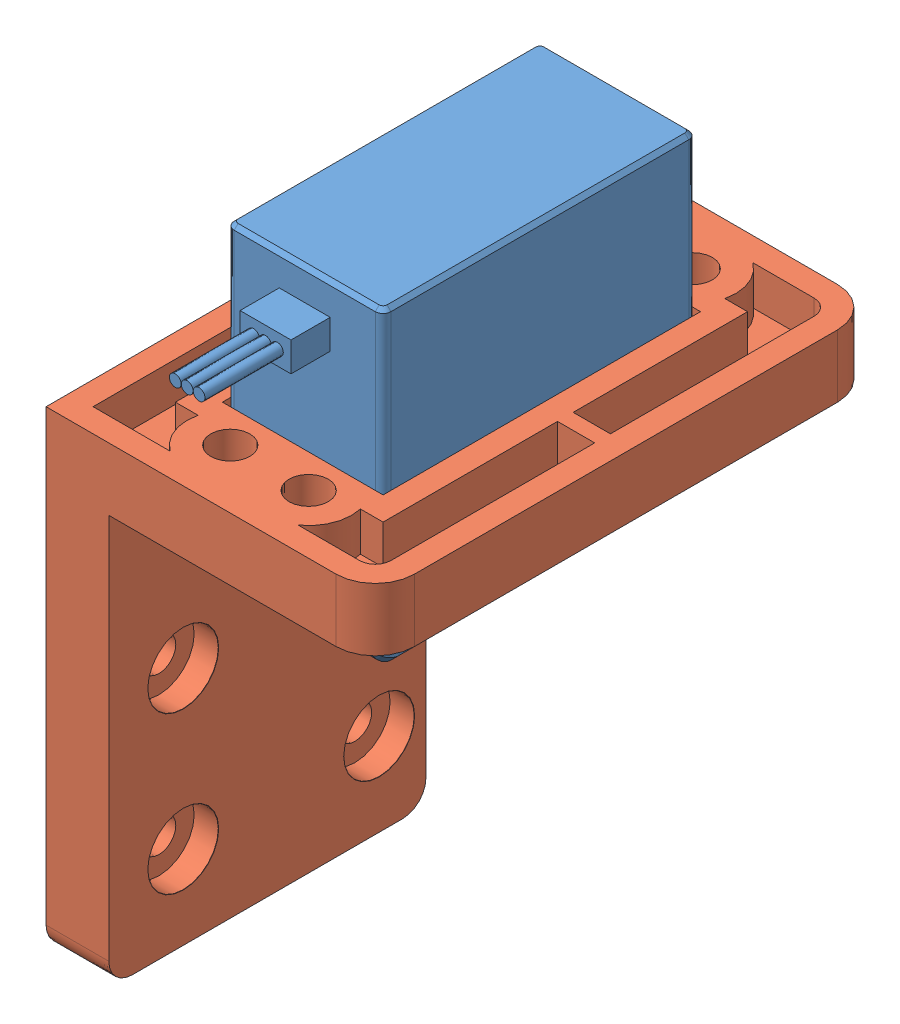
SolidWorks assembly SERVO_MotorASSEM_Cpt2, configuration Default. Lengths in mm.
Overall size (42 80.28 67).
2 component instances, 2 part files, 3 mates.
Components (placement in the parent):
- ServoMotor_DS3240MG.step-1: ServoMotor_DS3240MG.step [Default] at (282.8766 429.2463 295.9546) x (0 0 1) z (1 0 0) size (62 45 20)
- Bracket-1: Bracket [Default] at (60.5975 343.4703 288.4921) size (42 60.28 64)
Mates (geometry in assembly coordinates):
- Width1: width anti-aligned: plane of Bracket-1 through (272.6266 392.7463 316.2046) normal (1 0 0); plane of Bracket-1 through (293.1266 392.7463 316.2046) normal (-1 0 0); plane of ServoMotor_DS3240MG.step-1 through (272.8766 383.7463 275.9546) normal (-1 0 0); plane of ServoMotor_DS3240MG.step-1 through (292.8766 383.7463 275.9546) normal (1 0 0)
- Coincident1: coincident anti-aligned: plane of ServoMotor_DS3240MG.step-1 through (272.8666 395.7463 275.9546) normal (0 1 0); plane of Bracket-1 through (303.8866 395.7463 279.4835) normal (0 -1 0)
- Concentric1: concentric anti-aligned: cylinder of ServoMotor_DS3240MG.step-1 through (277.8766 429.2463 320.4546) axis (0 -1 0) radius 2.1; cylinder of Bracket-1 through (277.8766 343.4703 320.4546) axis (0 1 0) radius 2.1
